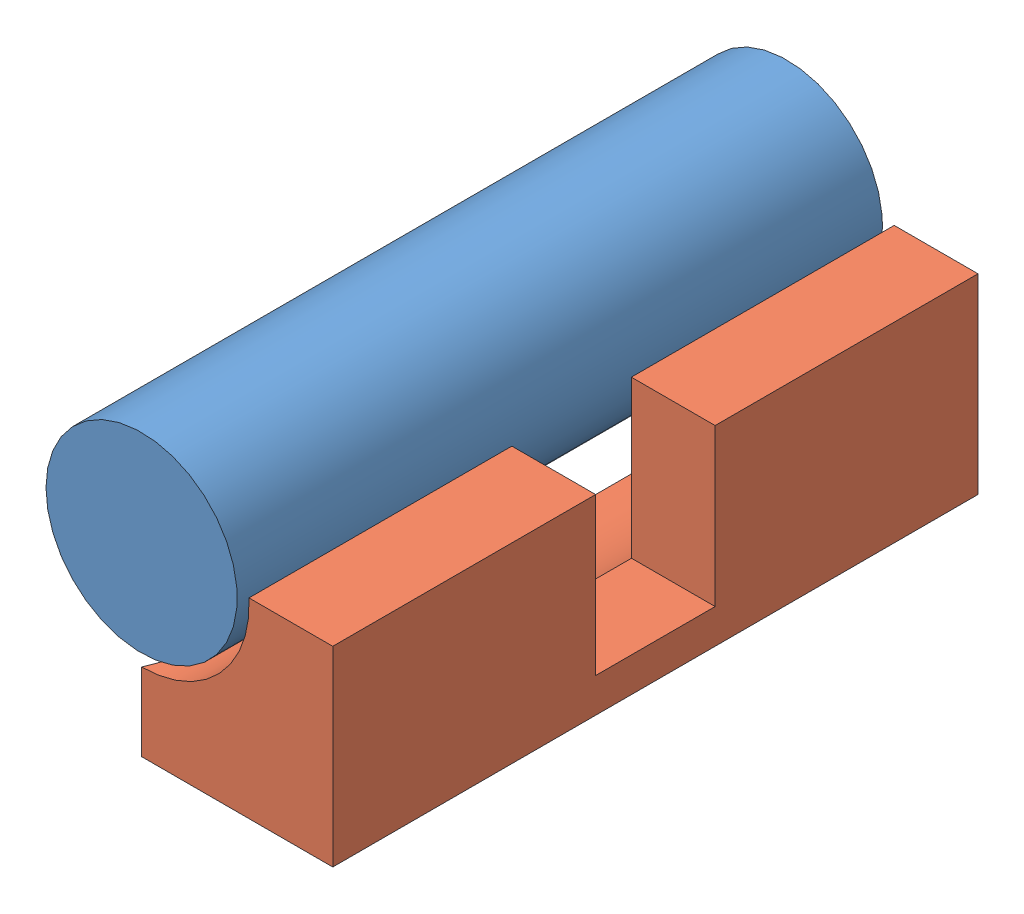
SolidWorks assembly Collection 2 Rough Assembly, configuration Default. Lengths in mm.
Overall size (120 117.5 270).
2 component instances, 2 part files, 6 mates.
Components (placement in the parent):
- Brush - rough-1: Brush - rough [bigger] at (-40 77.5 -135) size (80 80 270)
- Ball Guide 2 - rough-1: Ball Guide 2 - rough [Default] x (0 0 1) z (-1 0 0) size (270 80 80)
Mates (geometry in assembly coordinates):
- Coincident3: coincident: plane of Brush - rough-1 through (-40 77.5 0) normal (0 0 1); moEndPointRef_w of Ball Guide 2 - rough-1
- Parallel1: parallel aligned: plane of Brush - rough-1 through (-40 77.5 -135) normal (0 1 0); plane of Ball Guide 2 - rough-1
- Coincident6: coincident aligned: plane of Ball Guide 2 - rough-1 through (0 0 0) normal (0 0 1); plane of assembly through (0 0 0) normal (0 0 1)
- Coincident7: coincident aligned: plane of Ball Guide 2 - rough-1; plane of assembly through (0 0 0) normal (0 1 0)
- Coincident8: coincident anti-aligned: plane of Ball Guide 2 - rough-1 through (0 0 0) normal (-1 0 0); plane of assembly through (0 0 0) normal (1 0 0)
- Concentric1: concentric anti-aligned: cylinder of Brush - rough-1 through (-40 77.5 135) axis (0 0 -1) radius 40; cylinder of Ball Guide 2 - rough-1 through (-40 77.5 -135) axis (0 0 1) radius 45
